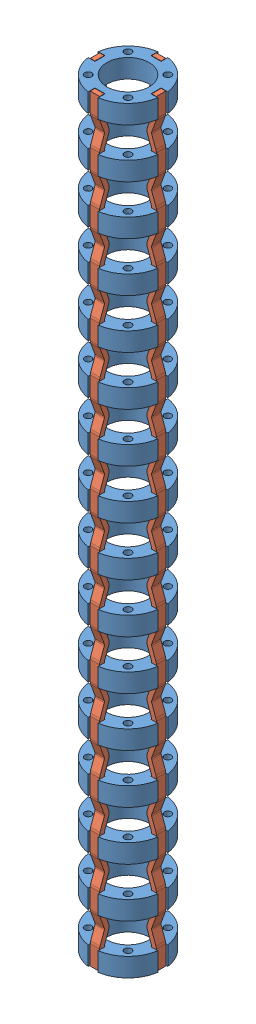
SolidWorks assembly Spine3Segments, configuration Default. Lengths in mm.
Overall size (14.85 161.57 14.85).
20 component instances, 2 part files, 9 mates.
Components (placement in the parent):
- RigidDisc-1: RigidDisc [Default] at (4.4669 6.9477 12.6403) size (14.85 4 14.85)
- Ligament-9: Ligament [Default] at (11.0169 10.9477 11.6403) x (0 -1 0) z (-1 0 0) size (161.57 2 2.03)
- RigidDisc-2: RigidDisc [Default] at (4.4669 -3.5523 12.6403) size (14.85 4 14.85)
- RigidDisc-3: RigidDisc [Default] at (4.4669 -14.0523 12.6403) size (14.85 4 14.85)
- RigidDisc-4: RigidDisc [Default] at (4.4669 -24.5523 12.6403) size (14.85 4 14.85)
- RigidDisc-5: RigidDisc [Default] at (4.4669 -35.0523 12.6403) size (14.85 4 14.85)
- RigidDisc-16: RigidDisc [Default] at (4.4669 -45.5523 12.6403) size (14.85 4 14.85)
- RigidDisc-17: RigidDisc [Default] at (4.4669 -56.0523 12.6403) size (14.85 4 14.85)
- RigidDisc-18: RigidDisc [Default] at (4.4669 -66.5523 12.6403) size (14.85 4 14.85)
- RigidDisc-19: RigidDisc [Default] at (4.4669 -77.0523 12.6403) size (14.85 4 14.85)
- RigidDisc-20: RigidDisc [Default] at (4.4669 -87.5523 12.6403) size (14.85 4 14.85)
- RigidDisc-21: RigidDisc [Default] at (4.4669 -98.0523 12.6403) size (14.85 4 14.85)
- RigidDisc-22: RigidDisc [Default] at (4.4669 -108.5523 12.6403) size (14.85 4 14.85)
- RigidDisc-23: RigidDisc [Default] at (4.4669 -119.0523 12.6403) size (14.85 4 14.85)
- RigidDisc-24: RigidDisc [Default] at (4.4669 -129.5523 12.6403) size (14.85 4 14.85)
- RigidDisc-25: RigidDisc [Default] at (4.4669 -140.0523 12.6403) size (14.85 4 14.85)
- RigidDisc-26: RigidDisc [Default] at (4.4669 -150.5523 12.6403) size (14.85 4 14.85)
- Ligament-11: Ligament [Default] at (3.4669 10.9477 6.0903) x (0 -1 0) z (0 0 1) size (161.57 2 2.03)
- Ligament-12: Ligament [Default] at (-2.0831 10.9477 13.6403) x (0 -1 0) z (1 0 0) size (161.57 2 2.03)
- Ligament-13: Ligament [Default] at (5.4669 10.9477 19.1903) x (0 -1 0) z (0 0 -1) size (161.57 2 2.03)
Mates (geometry in assembly coordinates):
- Coincident21: coincident anti-aligned: plane of RigidDisc-1 through (4.4669 6.9477 13.7153) normal (0 0 -1); plane of Ligament-5 through (-1.0081 -150.626 13.7153) normal (0 0 1)
- Coincident23: coincident anti-aligned: plane of RigidDisc-1 through (-1.5081 6.9477 11.5653) normal (-1 0 0); plane of Ligament-5 through (-1.5081 -188.4786 11.7153) normal (1 0 0)
- Coincident25: coincident anti-aligned: plane of RigidDisc-1 through (3.3919 6.9477 12.6403) normal (1 0 0); plane of Ligament-8 through (3.3919 -150.626 7.1653) normal (-1 0 0)
- Coincident26: coincident anti-aligned: plane of RigidDisc-1 through (5.5419 6.9477 6.6653) normal (0 0 -1); plane of Ligament-8 through (5.3919 -188.4786 6.6653) normal (0 0 1)
- Distance2: distance = 0.075 mm anti-aligned: plane of RigidDisc-1 through (10.4419 6.9477 13.7153) normal (1 0 0); plane of Ligament-9 through (10.5169 -30.9786 13.6403) normal (-1 0 0)
- Distance1: distance = 0.075 mm anti-aligned: plane of RigidDisc-1 through (4.4669 6.9477 11.5653) normal (0 0 1); plane of Ligament-9 through (10.0169 6.874 11.6403) normal (0 0 -1)
- Coincident32: coincident anti-aligned: plane of RigidDisc-1 through (3.3919 6.9477 18.6153) normal (0 0 1); plane of Ligament-10 through (3.5419 -188.4786 18.6153) normal (0 0 -1)
- Coincident33: coincident anti-aligned: plane of RigidDisc-1 through (5.5419 6.9477 12.6403) normal (-1 0 0); plane of Ligament-10 through (5.5419 -150.626 18.1153) normal (1 0 0)
- Coincident34: coincident aligned: plane of RigidDisc-1 through (4.4669 10.9477 12.6403) normal (0 1 0); plane of Ligament-9 through (11.5169 10.9477 13.6403) normal (0 1 0)
